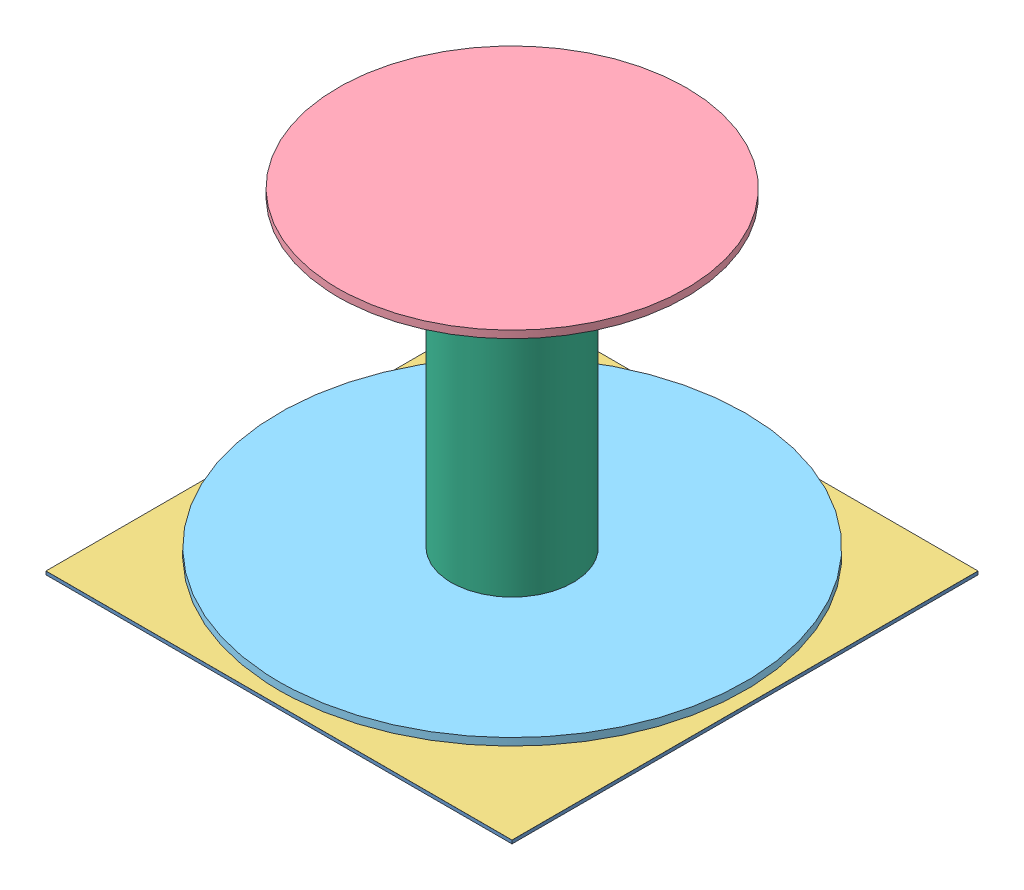
SolidWorks assembly Assem2, configuration Default. Lengths in mm.
Overall size (53.54 38.49 53.55).
6 component instances, 6 part files, 9 mates.
Components (placement in the parent):
- Dielectric Quarter-1: Dielectric Quarter [Default] at (-62.0822 13.8841 118.9716) size (53.53 0.38 53.53)
- Feed Network Quarter-1: Feed Network Quarter [Default] at (-57.793 14.0596 63.9465) size (48.43 0.01 21.5)
- Ground Plane Quarter-1: Ground Plane Quarter [Default] at (-61.8299 14.4506 118.719) size (53.53 0.01 53.53)
- Parasitic SAP Quarter-1: Parasitic SAP Quarter [Default] at (-8.5401 51.2796 65.4215) size (40 0.85 40)
- SAP Quarter-1: SAP Quarter [Default] at (-8.5401 15.5306 65.4215) size (53.53 0.85 53.53)
- Tower Quarter-1: Tower Quarter [Default] at (-8.5401 -4.1689 65.4215) size (14 37.25 14)
Mates (geometry in assembly coordinates):
- Coincident1: coincident: point of Dielectric Quarter-1; point of Ground Plane Quarter-1
- Coincident2: coincident anti-aligned: plane of Parasitic SAP Quarter-1 through (-8.5401 51.7046 65.4215) normal (0 -1 0); plane of Tower Quarter-1 through (-8.5401 51.7046 65.4215) normal (0 1 0)
- Concentric1: concentric aligned: circle of Parasitic SAP Quarter-1; circle of Tower Quarter-1
- Distance1: distance = 1.5 mm aligned: plane of SAP Quarter-1 through (-8.5401 15.9556 65.4215) normal (0 -1 0); plane of Tower Quarter-1 through (-8.5401 14.4556 65.4215) normal (0 -1 0)
- Concentric2: concentric aligned: circle of SAP Quarter-1; circle of Tower Quarter-1
- Concentric3: concentric anti-aligned: circle of Ground Plane Quarter-1; circle of Tower Quarter-1
- Distance3: distance = 22.265 mm: point of Feed Network Quarter-1; point of Dielectric Quarter-1
- Coincident10: coincident: plane of Dielectric Quarter-1 through (-35.3147 14.0746 92.2041) normal (0 -1 0); plane of Feed Network Quarter-1 through (-36.2689 14.0746 61.9136) normal (0 1 0)
- Coincident12: coincident aligned: line of Dielectric Quarter-1 through (-35.3147 14.0746 38.6691) axis (0 0 1); line of Feed Network Quarter-1 through (-35.3147 14.0746 60.9341) axis (0 0 1)
